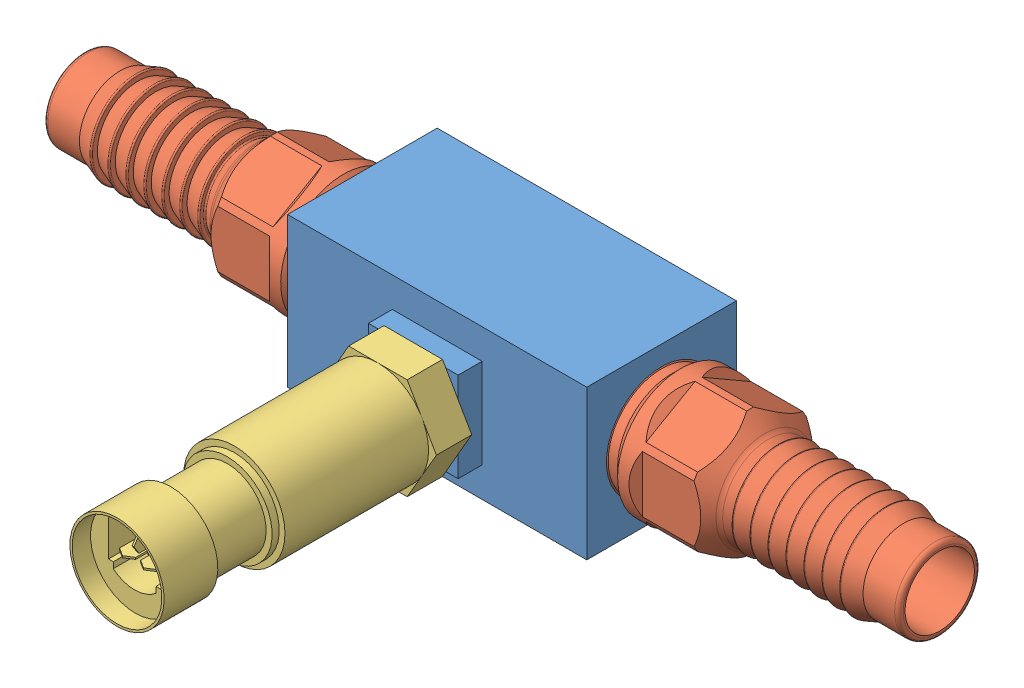
SolidWorks assembly Aluminum Adapter Subassembly, configuration Default. Lengths in mm.
Overall size (181.56 31.75 99.71).
4 component instances, 3 part files, 6 mates.
Components (placement in the parent):
- EN10114-AA-Aluminum Adapter-1: EN10114-AA-Aluminum Adapter [Default] at (-116.0168 -17.6659 59.8867) size (63.5 31.75 36.83)
- EN10111-AA-0.75in Easy-Fit Barbed Hose Fitting (5363K52)-1: EN10111-AA-0.75in Easy-Fit Barbed Hose Fitting (5363K52) [5363K52] at (-64.9223 -1.7909 59.8867) x (0 0 -1) z (1 0 0) size (26.67 28.88 79.38)
- EN10111-AA-0.75in Easy-Fit Barbed Hose Fitting (5363K52)-2: EN10111-AA-0.75in Easy-Fit Barbed Hose Fitting (5363K52) [5363K52] at (-167.1114 -1.7909 59.8867) x (0 0 1) z (-1 0 0) size (26.67 28.88 79.38)
- EN-10202-AA-Pressure and Temperature Transducer, Transducers Direct-1: EN-10202-AA-Pressure and Temperature Transducer, Transducers Direct [Default] at (-116.0168 -1.7909 70.5417) x (1 0 0) z (0 -1 0) size (24.83 73.18 21.5)
Mates (geometry in assembly coordinates):
- Concentric1: concentric aligned: cylinder of EN10114-AA-Aluminum Adapter-1 through (-84.2668 -1.7909 59.8867) axis (1 0 0) radius 11.7079; cylinder of EN10111-AA-0.75in Easy-Fit Barbed Hose Fitting (5363K52)-1 through (-25.2348 -1.7909 59.8867) axis (1 0 0) radius 7.366
- Coincident1: coincident anti-aligned: plane of EN10114-AA-Aluminum Adapter-1 through (-84.2668 14.0841 59.8867) normal (1 0 0); circle of EN10111-AA-0.75in Easy-Fit Barbed Hose Fitting (5363K52)-1
- Concentric2: concentric anti-aligned: cylinder of EN10114-AA-Aluminum Adapter-1 through (-84.2668 -1.7909 59.8867) axis (1 0 0) radius 11.7079; cylinder of EN10111-AA-0.75in Easy-Fit Barbed Hose Fitting (5363K52)-2 through (-206.7989 -1.7909 59.8867) axis (-1 0 0) radius 7.366
- Coincident2: coincident anti-aligned: plane of EN10114-AA-Aluminum Adapter-1 through (-147.7668 14.0841 59.8867) normal (-1 0 0); circle of EN10111-AA-0.75in Easy-Fit Barbed Hose Fitting (5363K52)-2
- Concentric3: concentric: cylinder of EN10114-AA-Aluminum Adapter-1 through (-116.0168 -1.7909 80.8417) axis (0 0 1) radius 5.5563; cylinder of EN-10202-AA-Pressure and Temperature Transducer, Transducers Direct-1 through (-116.0168 -1.7909 80.8417) axis (0 0 -1) radius 5.1435
- Coincident3: coincident anti-aligned: plane of EN10114-AA-Aluminum Adapter-1 through (-116.0168 -17.6659 80.8417) normal (0 0 1); plane of EN-10202-AA-Pressure and Temperature Transducer, Transducers Direct-1 through (-116.0168 -1.7909 80.8417) normal (0 0 -1)
